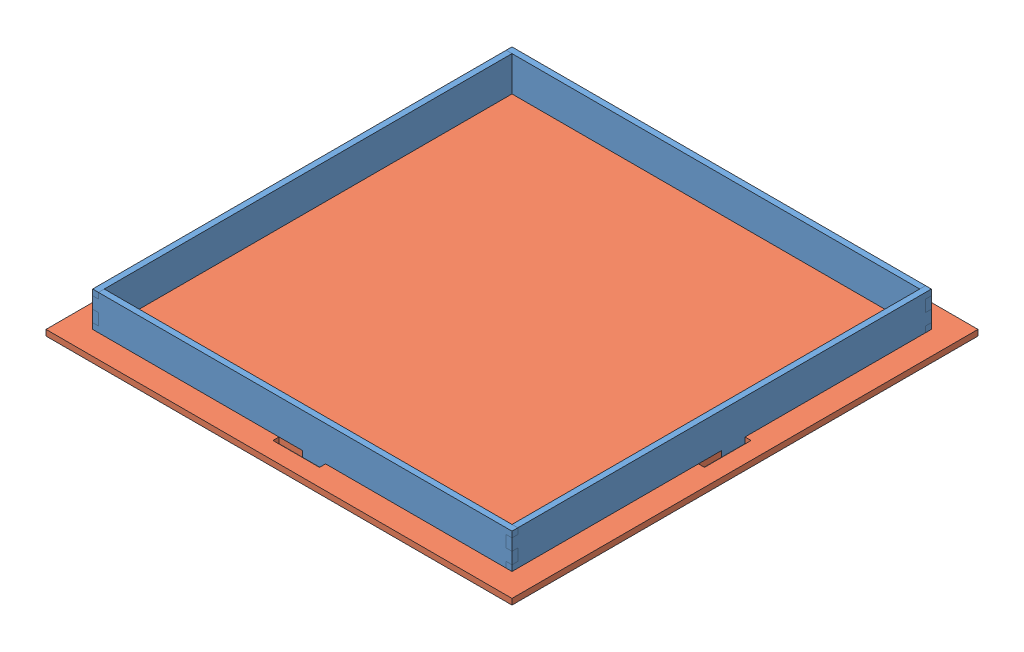
SolidWorks assembly bottomAssemblyV2, configuration Default. Lengths in mm.
Overall size (254 22.23 254).
5 component instances, 2 part files, 12 mates.
Components (placement in the parent):
- bottomWall-1: bottomWall [Default] at (-30.7017 2.8103 12.7916) size (228.6 22.23 3.17)
- bottomWall-2: bottomWall [Default] at (80.4233 2.8103 -98.3334) x (0 0 -1) z (1 0 0) size (228.6 22.23 3.17)
- bottomWall-3: bottomWall [Default] at (-30.7017 2.8103 -209.4584) x (-1 0 0) z (0 0 -1) size (228.6 22.23 3.17)
- bottomWall-4: bottomWall [Default] at (-141.8267 2.8103 -98.3334) x (0 0 1) z (-1 0 0) size (228.6 22.23 3.17)
- bottomFloor-1: bottomFloor [Default] at (-30.7017 -6.7147 -98.3334) x (-1 0 0) z (0 0 1) size (254 3.17 254)
Mates (geometry in assembly coordinates):
- Coincident1: coincident anti-aligned: plane of bottomWall-1 through (-30.7017 2.8103 12.7916) normal (0 0 -1); plane of bottomWall-4 through (-145.0017 2.8103 12.7916) normal (0 0 1)
- Coincident2: coincident aligned: plane of bottomWall-4 through (-145.0017 2.8103 -98.3334) normal (-1 0 0); plane of bottomWall-1 through (-145.0017 2.8103 15.9666) normal (-1 0 0)
- Coincident6: coincident anti-aligned: plane of bottomWall-1 through (-30.7017 2.8103 15.9666) normal (0 1 0); plane of bottomWall-2 through (83.5983 2.8103 -98.3334) normal (0 -1 0)
- Coincident7: coincident anti-aligned: plane of bottomWall-3 through (-30.7017 2.8103 -209.4584) normal (0 0 1); plane of bottomWall-4 through (-145.0017 2.8103 -209.4584) normal (0 0 -1)
- Coincident8: coincident anti-aligned: plane of bottomWall-3 through (-141.8267 2.8103 -212.6334) normal (-1 0 0); plane of bottomWall-4 through (-141.8267 2.8103 -98.3334) normal (1 0 0)
- Coincident20: coincident aligned: plane of bottomWall-2 through (83.5983 -9.8897 -98.3334) normal (0 -1 0); plane of bottomFloor-1 through (-30.7017 -9.8897 -98.3334) normal (0 -1 0)
- Coincident22: coincident aligned: plane of bottomWall-3 through (-30.7017 -9.8897 -212.6334) normal (0 -1 0); plane of bottomFloor-1 through (-30.7017 -9.8897 -98.3334) normal (0 -1 0)
- Coincident23: coincident aligned: plane of bottomWall-4 through (-145.0017 -9.8897 -98.3334) normal (0 -1 0); plane of bottomFloor-1 through (-30.7017 -9.8897 -98.3334) normal (0 -1 0)
- Coincident26: coincident anti-aligned: plane of bottomWall-3 through (-30.7017 2.8103 -212.6334) normal (0 0 -1); plane of bottomFloor-1 through (-30.7017 -9.8897 -212.6334) normal (0 0 1)
- Coincident27: coincident anti-aligned: plane of bottomWall-2 through (83.5983 2.8103 -98.3334) normal (1 0 0); plane of bottomFloor-1 through (83.5983 -9.8897 -98.3334) normal (-1 0 0)
- Coincident28: coincident anti-aligned: plane of bottomWall-4 through (-145.0017 2.8103 -98.3334) normal (-1 0 0); plane of bottomFloor-1 through (-145.0017 -9.8897 -98.3334) normal (1 0 0)
- Coincident29: coincident aligned: plane of bottomWall-2 through (83.5983 2.8103 -212.6334) normal (0 0 -1); plane of bottomWall-3 through (-30.7017 2.8103 -212.6334) normal (0 0 -1)
